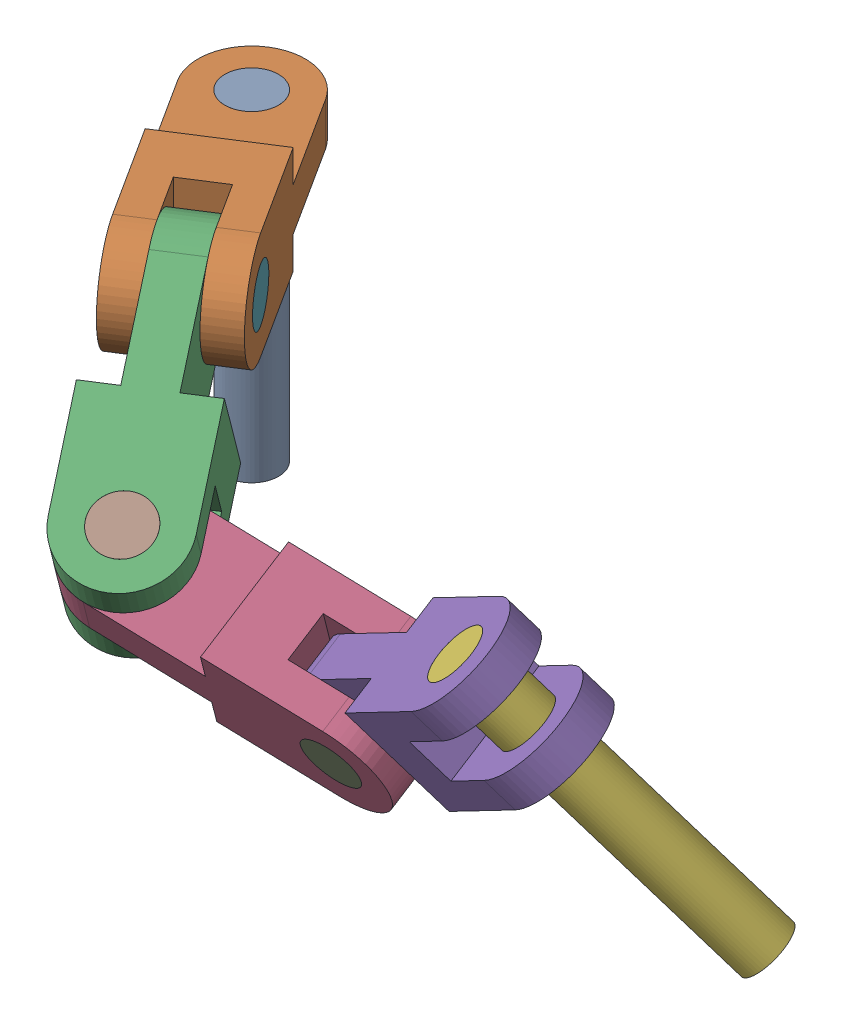
SolidWorks assembly Assemblage2_b, configuration Défaut. Lengths in mm.
Overall size (795.63 348.3 467.9).
9 component instances, 3 part files, 20 mates.
Components (placement in the parent):
- long_pin-2: long_pin [Default] at origin size (50 300 50)
- chain_link-2: chain_link [Default] at (53.9007 -20 84.2301) x (0 -1 0) z (-0.842301 0 0.539007) size (100 300 100)
- chain_link-3: chain_link [Default] at (154.4809 -70 241.4056) x (0.842301 0 -0.539007) z (-0.269504 -0.866025 -0.421151) size (100 300 100)
- chain_link-4: chain_link [Default] at (297.2263 -141.1309 296.3284) x (0.269504 0.866025 0.421151) z (-0.067087 0.453154 -0.888904) size (100 300 100)
- chain_link-5: chain_link [Default] at (475.6874 -109.5031 298.9831) x (0.067087 -0.453154 0.888904) z (-0.562674 0.718543 0.408771) size (100 300 100)
- long_pin-3: long_pin [Default] at (529.9489 -20.8173 340.099) x (0.73599 0.660593 -0.148105) z (0.376451 -0.217517 0.900539) size (50 300 50)
- short_pin-1: short_pin [Default] at (149.9165 -20 141.5098) x (0.290529 -0.842301 0.454006) z (0.454006 0.539007 0.709471) size (50 100 50)
- short_pin-2: short_pin [Default] at (214.6355 -76.6987 335.4085) x (0.961076 -0.269504 -0.060825) z (-0.060825 -0.421151 0.904949) size (50 100 50)
- short_pin-3: short_pin [Default] at (396.6466 -184.9195 322.751) x (0.99177 -0.067087 -0.109051) z (-0.109051 -0.888904 -0.444924) size (50 100 50)
Mates (geometry in assembly coordinates):
- Coaxiale2: concentric anti-aligned: cylinder of long_pin-2 through (0 -300 0) axis (0 1 0) radius 25; cylinder of chain_link-2 through (0 30 0) axis (0 -1 0) radius 25
- Coïncidente1: coincident aligned: plane of long_pin-2 through (0 0 0) normal (0 1 0); plane of chain_link-2 through (0 0 0) normal (0 1 0)
- Coïncidente2: coincident anti-aligned: circle of chain_link-2; cylinder of chain_link-3 through (65.6864 -20 195.4106) axis (0.842301 0 -0.539007) radius 25
- Coïncidente3: coincident anti-aligned: plane of chain_link-2 through (117.9058 30 221.3554) normal (0.842301 0 -0.539007); plane of chain_link-3 through (90.9555 -20 179.2404) normal (-0.842301 0 0.539007)
- Angle1: planar angle = 0.523599 rad aligned: plane of chain_link-3 through (214.6355 -76.6987 335.4085) normal (0.269504 0.866025 0.421151); plane of chain_link-2 through (11.7857 30 111.1805) normal (0 1 0)
- Coaxiale3: concentric anti-aligned: cylinder of chain_link-3 through (187.6851 123.3013 293.2935) axis (0.269504 -0.866025 0.421151) radius 25; cylinder of chain_link-4 through (214.6355 36.6987 335.4086) axis (-0.269504 0.866025 -0.421151) radius 25
- Coïncidente5: coincident anti-aligned: plane of chain_link-3 through (176.9949 122.3205 369.3511) normal (0.269504 -0.866025 0.421151); plane of chain_link-4 through (195.7702 97.3205 305.928) normal (-0.269504 0.866025 -0.421151)
- Angle2: planar angle = 2.007129 rad anti-aligned: plane of chain_link-3 through (183.1208 -113.3013 193.3977) normal (0.842301 0 -0.539007); plane of chain_link-4 through (389.9379 -139.6041 233.8606) normal (-0.067087 0.453154 -0.888904)
- Coaxiale4: concentric anti-aligned: cylinder of chain_link-4 through (396.6466 144.9195 322.751) axis (-0.067087 -0.453154 -0.888904) radius 25; cylinder of chain_link-5 through (389.9379 99.6041 233.8606) axis (0.067087 0.453154 0.888904) radius 25
- Coïncidente7: coincident anti-aligned: plane of chain_link-4 through (456.1422 98.5891 308.1301) normal (-0.067087 -0.453154 -0.888904); plane of chain_link-5 through (394.634 131.3249 296.0839) normal (0.067087 0.453154 0.888904)
- Angle3: planar angle = 2.268928 rad anti-aligned: plane of chain_link-5 through (529.9489 -20.8173 340.099) normal (-0.562674 0.718543 0.408771); plane of chain_link-4 through (307.3471 -75.1719 272.9407) normal (0.269504 0.866025 0.421151)
- Coaxiale5: concentric aligned: cylinder of chain_link-5 through (520.959 262.3701 197.2449) axis (-0.909142 0.394798 -0.132649) radius 25; cylinder of long_pin-3 through (702.7873 183.4104 223.7747) axis (-0.909142 0.394798 -0.132649) radius 25
- Coïncidente9: coincident aligned: plane of chain_link-5 through (430.0448 301.8499 183.98) normal (-0.909142 0.394798 -0.132649); plane of long_pin-3 through (430.0448 301.8499 183.98) normal (-0.909142 0.394798 -0.132649)
- Coaxiale6: concentric anti-aligned: cylinder of chain_link-2 through (149.9165 -20 141.5098) axis (-0.842301 0 0.539007) radius 25; cylinder of short_pin-1 through (65.6864 -20 195.4106) axis (0.842301 0 -0.539007) radius 25
- Coïncidente10: coincident aligned: plane of chain_link-2 through (149.9165 -20 141.5098) normal (0.842301 0 -0.539007); plane of short_pin-1 through (149.9165 -20 141.5098) normal (0.842301 0 -0.539007)
- Coaxiale7: concentric anti-aligned: cylinder of chain_link-3 through (187.6851 123.3013 293.2935) axis (0.269504 -0.866025 0.421151) radius 25; cylinder of short_pin-2 through (214.6355 36.6987 335.4085) axis (-0.269504 0.866025 -0.421151) radius 25
- Coïncidente11: coincident aligned: plane of chain_link-3 through (187.6851 123.3013 293.2935) normal (-0.269504 0.866025 -0.421151); plane of short_pin-2 through (187.6851 123.3013 293.2935) normal (-0.269504 0.866025 -0.421151)
- Coaxiale9: concentric anti-aligned: cylinder of chain_link-4 through (396.6466 144.9195 322.751) axis (-0.067087 -0.453154 -0.888904) radius 25; cylinder of short_pin-3 through (389.9379 99.6041 233.8606) axis (0.067087 0.453154 0.888904) radius 25
- Coïncidente15: coincident aligned: plane of chain_link-4 through (396.6466 144.9195 322.751) normal (0.067087 0.453154 0.888904); plane of short_pin-3 through (396.6466 144.9195 322.751) normal (0.067087 0.453154 0.888904)
- Coïncidente17: coincident: plane of assembly; plane of long_pin-2 through (0 0 0) normal (0 1 0); point of assembly
